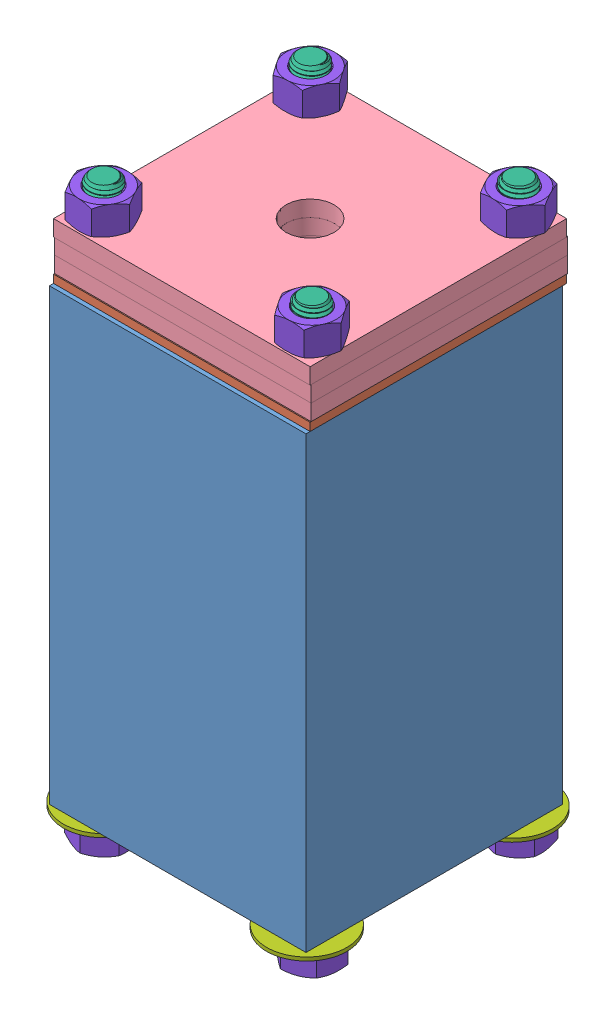
SolidWorks assembly ModularPayloadBox, configuration Default. Lengths in mm.
Overall size (114.3 271.03 114.25).
26 component instances, 8 part files, 40 mates.
Components (placement in the parent):
- Modular_Box_Main-1: Modular_Box_Main [Default] at (-71.2305 22.1106 4.3677) size (101.6 177.86 101.6)
- BoxLid_Drawer-1: BoxLid_Drawer [Default] at (-33.5282 101.5437 55.2222) x (0 0 -1) z (0 -1 0) size (101.6 101.6 168.28)
- Steel_Side_Plates-1: Steel_Side_Plates [Default] at (-65.9397 -76.3144 34.0019) size (6.35 172.51 61.38)
- Steel_Top_Plate-1: Steel_Top_Plate [Default] at (-71.2305 101.5437 -48.4786) x (0 0 1) z (-1 0 0) size (101.6 6.35 101.6)
- Steel_Side_Plates-2: Steel_Side_Plates [Default] at (11.3714 -76.3144 49.8769) x (0 0 -1) z (1 0 0) size (6.35 172.51 61.38)
- Steel_Side_Plates-3: Steel_Side_Plates [Default] at (18.7279 -76.3144 36.1177) size (6.35 172.51 61.38)
- Steel_Side_Plates-4: Steel_Side_Plates [Default] at (9.2037 -76.3144 -34.7914) x (0 0 -1) z (1 0 0) size (6.35 172.51 61.38)
- BulkHead-1: BulkHead [Default] at (-20.4045 -63.3604 4.3677) size (38.34 72.79 38.07)
- Steel_Top_Plate-2: Steel_Top_Plate [Default] at (-71.2305 107.8937 -48.4786) x (0 0 1) z (-1 0 0) size (101.6 6.35 101.6)
- Steel_Top_Plate-3: Steel_Top_Plate [Default] at (30.3695 114.2437 53.5393) x (0 0 -1) z (1 0 0) size (101.6 6.35 101.6)
- 98817A270_LOW-STRENGTH STEEL LEFT-HAND THREADED ROD-3: 98817A270_LOW-STRENGTH STEEL LEFT-HAND THREADED ROD [98817A270] at (-61.7055 19.9531 43.2732) x (0 1 0) z (0 0 1) size (233.29 12.2 13.88)
- 90107A033_TYPE 316 STAINLESS STEEL FLAT WASHER-1: 90107A033_TYPE 316 STAINLESS STEEL FLAT WASHER [90107A033] at (20.8445 -80.8864 -36.1611) size (31.75 1.4 31.75)
- 90107A033_TYPE 316 STAINLESS STEEL FLAT WASHER-2: 90107A033_TYPE 316 STAINLESS STEEL FLAT WASHER [90107A033] at (-61.7055 -80.8864 -36.1611) size (31.75 1.4 31.75)
- 90107A033_TYPE 316 STAINLESS STEEL FLAT WASHER-3: 90107A033_TYPE 316 STAINLESS STEEL FLAT WASHER [90107A033] at (20.8445 -80.8864 45.3245) size (31.75 1.4 31.75)
- 90107A033_TYPE 316 STAINLESS STEEL FLAT WASHER-4: 90107A033_TYPE 316 STAINLESS STEEL FLAT WASHER [90107A033] at (-61.7055 -80.8864 43.2732) size (31.75 1.4 31.75)
- 95462A033_GRADE 5 STEEL HEX NUT-1: 95462A033_GRADE 5 STEEL HEX NUT [95462A033] at (-61.7055 -86.4426 43.2732) x (0.618745 0 0.785592) z (0 -1 0) size (19.05 22 14.07)
- 95462A033_GRADE 5 STEEL HEX NUT-2: 95462A033_GRADE 5 STEEL HEX NUT [95462A033] at (-61.7055 126.1499 43.2732) x (-0.837169 0 -0.546944) z (0 -1 0) size (19.05 22 14.07)
- 95462A033_GRADE 5 STEEL HEX NUT-3: 95462A033_GRADE 5 STEEL HEX NUT [95462A033] at (-61.7055 126.0835 -38.6303) x (-0.837169 0 0.546944) z (0 1 0) size (19.05 22 14.07)
- 98817A270_LOW-STRENGTH STEEL LEFT-HAND THREADED ROD-5: 98817A270_LOW-STRENGTH STEEL LEFT-HAND THREADED ROD [98817A270] at (-61.7055 19.9531 -38.6303) x (0 1 0) z (0 0 1) size (233.29 12.2 13.88)
- 95462A033_GRADE 5 STEEL HEX NUT-4: 95462A033_GRADE 5 STEEL HEX NUT [95462A033] at (-61.7055 -86.509 -38.6303) x (0.618745 0 -0.785592) z (0 1 0) size (19.05 22 14.07)
- 95462A033_GRADE 5 STEEL HEX NUT-5: 95462A033_GRADE 5 STEEL HEX NUT [95462A033] at (20.8445 -86.509 43.2732) x (-0.618745 0 0.785592) z (0 1 0) size (19.05 22 14.07)
- 98817A270_LOW-STRENGTH STEEL LEFT-HAND THREADED ROD-6: 98817A270_LOW-STRENGTH STEEL LEFT-HAND THREADED ROD [98817A270] at (20.8445 19.9531 43.2732) x (0 1 0) z (0 0 -1) size (233.29 12.2 13.88)
- 98817A270_LOW-STRENGTH STEEL LEFT-HAND THREADED ROD-7: 98817A270_LOW-STRENGTH STEEL LEFT-HAND THREADED ROD [98817A270] at (20.8445 19.9531 -38.6303) x (0 1 0) z (0 0 -1) size (233.29 12.2 13.88)
- 95462A033_GRADE 5 STEEL HEX NUT-6: 95462A033_GRADE 5 STEEL HEX NUT [95462A033] at (20.8445 -86.4426 -38.6303) x (-0.618745 0 -0.785592) z (0 -1 0) size (19.05 22 14.07)
- 95462A033_GRADE 5 STEEL HEX NUT-7: 95462A033_GRADE 5 STEEL HEX NUT [95462A033] at (20.8445 126.0835 43.2732) x (0.837169 0 -0.546944) z (0 1 0) size (19.05 22 14.07)
- 95462A033_GRADE 5 STEEL HEX NUT-8: 95462A033_GRADE 5 STEEL HEX NUT [95462A033] at (20.8445 126.1499 -38.6303) x (0.837169 0 0.546944) z (0 -1 0) size (19.05 22 14.07)
Mates (geometry in assembly coordinates):
- Parallel2: parallel anti-aligned: line of Modular_Box_Main-1 through (30.3695 98.3687 55.1677) axis (0 0 -1); line of BoxLid_Drawer-1 through (30.3695 101.5437 -48.0607) axis (0 0 1)
- Coincident9: coincident: plane of Modular_Box_Main-1 through (-71.2305 -76.3144 40.3519) normal (0 0 -1); plane of BoxLid_Drawer-1 through (-32.2415 -66.7313 40.3519) normal (0 0 1)
- Parallel3: parallel anti-aligned: line of Modular_Box_Main-1 through (-55.3555 98.3687 -30.5573) axis (0 0 -1); line of BoxLid_Drawer-1 through (-55.2963 101.5437 -44.8857) axis (0 0 1)
- Parallel4: parallel anti-aligned: line of Modular_Box_Main-1 through (-68.0555 98.3687 51.9927) axis (1 0 0); line of BoxLid_Drawer-1 through (-55.2963 101.5437 50.3643) axis (-1 0 0)
- Coincident12: coincident aligned: plane of Modular_Box_Main-1 through (-71.2305 22.1106 4.3677) normal (-1 0 0); plane of BoxLid_Drawer-1 through (-71.2305 98.3687 -48.0607) normal (-1 0 0)
- Parallel5: parallel anti-aligned: line of BoxLid_Drawer-1 through (-71.2305 98.3687 53.5393) axis (0 0 -1); line of Steel_Top_Plate-1 through (-71.2305 101.5437 -48.4786) axis (0 0 1)
- Coincident15: coincident anti-aligned: plane of Modular_Box_Main-1 through (-71.2305 -76.3144 4.3677) normal (0 1 0); plane of Steel_Side_Plates-3 through (25.0779 -76.3144 36.1177) normal (0 -1 0)
- Coincident16: coincident anti-aligned: plane of Modular_Box_Main-1 through (18.7279 -76.3144 4.3677) normal (1 0 0); plane of Steel_Side_Plates-3 through (18.7279 -76.3144 36.1177) normal (-1 0 0)
- Coincident17: coincident anti-aligned: plane of Modular_Box_Main-1 through (-71.2305 -76.3144 36.1177) normal (0 0 -1); plane of Steel_Side_Plates-3 through (25.0779 -76.3144 36.1177) normal (0 0 1)
- Coincident18: coincident anti-aligned: plane of Modular_Box_Main-1 through (-71.2305 -76.3144 4.3677) normal (0 1 0); plane of Steel_Side_Plates-1 through (-59.5897 -76.3144 34.0019) normal (0 -1 0)
- Coincident19: coincident anti-aligned: plane of Modular_Box_Main-1 through (-59.5897 -76.3144 4.3677) normal (-1 0 0); plane of Steel_Side_Plates-1 through (-59.5897 -76.3144 34.0019) normal (1 0 0)
- Coincident20: coincident anti-aligned: plane of Modular_Box_Main-1 through (-71.2305 -76.3144 -27.3823) normal (0 0 1); plane of Steel_Side_Plates-1 through (-59.5897 -76.3144 -27.3823) normal (0 0 -1)
- Coincident21: coincident anti-aligned: plane of Modular_Box_Main-1 through (11.3714 -76.3144 4.3677) normal (-1 0 0); plane of Steel_Side_Plates-2 through (11.3714 -76.3144 43.5269) normal (1 0 0)
- Coincident22: coincident anti-aligned: plane of Modular_Box_Main-1 through (-71.2305 -76.3144 43.5269) normal (0 0 1); plane of Steel_Side_Plates-2 through (11.3714 -76.3144 43.5269) normal (0 0 -1)
- Coincident23: coincident anti-aligned: plane of Modular_Box_Main-1 through (-71.2305 -76.3144 4.3677) normal (0 1 0); plane of Steel_Side_Plates-2 through (11.3714 -76.3144 43.5269) normal (0 -1 0)
- Coincident24: coincident anti-aligned: plane of Modular_Box_Main-1 through (-71.2305 -76.3144 4.3677) normal (0 1 0); plane of Steel_Side_Plates-4 through (9.2037 -76.3144 -41.1414) normal (0 -1 0)
- Coincident25: coincident anti-aligned: plane of Modular_Box_Main-1 through (-52.1805 -76.3144 4.3677) normal (1 0 0); plane of Steel_Side_Plates-4 through (-52.1805 -76.3144 -41.1414) normal (-1 0 0)
- Coincident26: coincident anti-aligned: plane of Modular_Box_Main-1 through (-71.2305 -76.3144 -34.7914) normal (0 0 -1); plane of Steel_Side_Plates-4 through (9.2037 -76.3144 -34.7914) normal (0 0 1)
- Coincident27: coincident anti-aligned: plane of BoxLid_Drawer-1 through (-33.5282 101.5437 55.2222) normal (0 1 0); plane of Steel_Top_Plate-1 through (-71.2305 101.5437 -48.4786) normal (0 -1 0)
- Concentric5: concentric anti-aligned: circle of Modular_Box_Main-1; circle of BulkHead-1
- Coincident29: coincident aligned: plane of Modular_Box_Main-1 through (30.3695 -79.4894 55.1677) normal (0 -1 0); circle of BulkHead-1
- Coincident30: coincident anti-aligned: plane of Steel_Top_Plate-1 through (-71.2305 107.8937 -48.4786) normal (0 1 0); plane of Steel_Top_Plate-2 through (-71.2305 107.8937 -48.4786) normal (0 -1 0)
- Coincident31: coincident anti-aligned: plane of Steel_Top_Plate-2 through (-71.2305 114.2437 -48.4786) normal (0 1 0); plane of Steel_Top_Plate-3 through (30.3695 114.2437 53.5393) normal (0 -1 0)
- Concentric8: concentric aligned: circle of Steel_Top_Plate-1; circle of Steel_Top_Plate-2
- Concentric9: concentric aligned: circle of Steel_Top_Plate-1; circle of Steel_Top_Plate-2
- Concentric10: concentric aligned: circle of Steel_Top_Plate-2; circle of Steel_Top_Plate-3
- Concentric11: concentric aligned: circle of Steel_Top_Plate-2; circle of Steel_Top_Plate-3
- Concentric12: concentric aligned: circle of BoxLid_Drawer-1; circle of Steel_Top_Plate-3
- Concentric14: concentric anti-aligned: circle of Steel_Top_Plate-3; circle of 98817A270_LOW-STRENGTH STEEL LEFT-HAND THREADED ROD-3
- Coincident42: coincident anti-aligned: plane of Modular_Box_Main-1 through (-71.2305 98.3687 55.1677) normal (0 1 0); plane of BoxLid_Drawer-1 through (-33.5282 98.3687 55.2222) normal (0 -1 0)
- Coincident44: coincident anti-aligned: plane of Modular_Box_Main-1 through (30.3695 -79.4894 55.1677) normal (0 -1 0); plane of 90107A033_TYPE 316 STAINLESS STEEL FLAT WASHER-1 through (20.8445 -79.4894 -36.1611) normal (0 1 0)
- Coincident46: coincident anti-aligned: plane of Modular_Box_Main-1 through (30.3695 -79.4894 55.1677) normal (0 -1 0); plane of 90107A033_TYPE 316 STAINLESS STEEL FLAT WASHER-3 through (20.8445 -79.4894 45.3245) normal (0 1 0)
- Coincident47: coincident anti-aligned: plane of Modular_Box_Main-1 through (30.3695 -79.4894 55.1677) normal (0 -1 0); plane of 90107A033_TYPE 316 STAINLESS STEEL FLAT WASHER-4 through (-61.7055 -79.4894 43.2732) normal (0 1 0)
- Concentric19: concentric anti-aligned: circle of 98817A270_LOW-STRENGTH STEEL LEFT-HAND THREADED ROD-3; circle of 90107A033_TYPE 316 STAINLESS STEEL FLAT WASHER-4
- Coincident48: coincident anti-aligned: plane of Modular_Box_Main-1 through (30.3695 -79.4894 55.1677) normal (0 -1 0); plane of 90107A033_TYPE 316 STAINLESS STEEL FLAT WASHER-2 through (-61.7055 -79.4894 -36.1611) normal (0 1 0)
- Concentric21: concentric anti-aligned: circle of 90107A033_TYPE 316 STAINLESS STEEL FLAT WASHER-4; circle of 95462A033_GRADE 5 STEEL HEX NUT-1
- Coincident49: coincident anti-aligned: plane of 90107A033_TYPE 316 STAINLESS STEEL FLAT WASHER-4 through (-61.7055 -80.8864 43.2732) normal (0 -1 0); plane of 95462A033_GRADE 5 STEEL HEX NUT-1 through (-71.9192 -80.8864 39.193) normal (0 1 0)
- Distance1: distance = 3.048 mm aligned: plane of 98817A270_LOW-STRENGTH STEEL LEFT-HAND THREADED ROD-3 through (-61.7055 -95.0469 43.2732) normal (0 -1 0); plane of 95462A033_GRADE 5 STEEL HEX NUT-1 through (-71.9192 -91.9989 39.193) normal (0 -1 0)
- Coincident51: coincident anti-aligned: plane of Steel_Top_Plate-3 through (30.3695 120.5937 53.5393) normal (0 1 0); plane of 95462A033_GRADE 5 STEEL HEX NUT-2 through (-50.7237 120.5937 43.879) normal (0 -1 0)
- Concentric22: concentric anti-aligned: circle of 98817A270_LOW-STRENGTH STEEL LEFT-HAND THREADED ROD-3; circle of 95462A033_GRADE 5 STEEL HEX NUT-2
